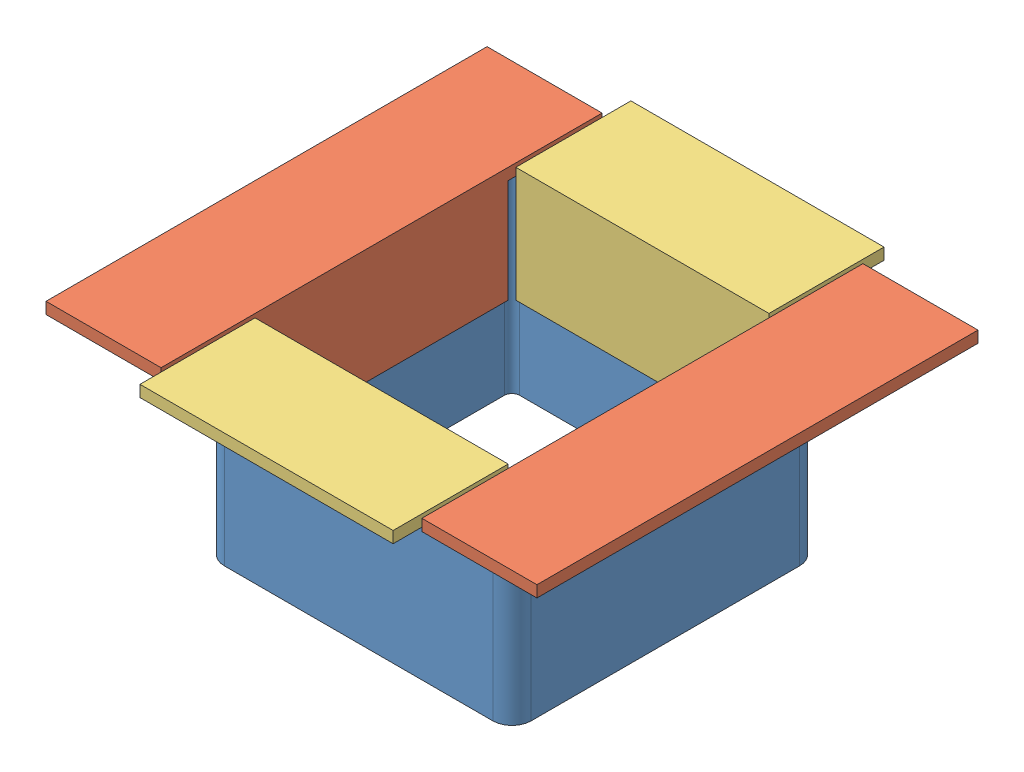
SolidWorks assembly ПяткаПСБ, configuration По умолчанию. Lengths in mm.
Overall size (128 54 128).
5 component instances, 3 part files, 6 mates.
Components (placement in the parent):
- Профиль80-1: Профиль80 [По умолчанию] at origin size (80 50 80)
- УголокДК2-1: УголокДК2 [По умолчанию] at (34 54 57.5) x (1 0 0) z (0 0 -1) size (30 30 115)
- УголокДК2-3: УголокДК2 [По умолчанию] at (-34 54 -57.5) x (-1 0 0) z (0 0 1) size (30 30 115)
- УголокДК1-1: УголокДК1 [По умолчанию] at (-33 54 34) x (0 0 1) z (1 0 0) size (30 30 66)
- УголокДК1-2: УголокДК1 [По умолчанию] at (33 54 -34) x (0 0 -1) z (-1 0 0) size (30 30 66)
Mates (geometry in assembly coordinates):
- Совпадение2: coincident anti-aligned: plane of Профиль80-1 through (37 50 -35) normal (-1 0 0); plane of УголокДК2-1 through (37 24 -61.5) normal (1 0 0)
- Расстояние1: distance = 1 mm anti-aligned: plane of УголокДК2-1 through (37 51 -57.5) normal (0 -1 0); plane of Профиль80-1 through (-35 50 35) normal (0 1 0)
- Совпадение4: coincident anti-aligned: plane of Профиль80-1 through (-35 50 37) normal (0 0 -1); plane of УголокДК1-1 through (33 24 37) normal (0 0 1)
- Совпадение5: coincident aligned: plane of УголокДК2-3 through (-34 54 61.5) normal (0 1 0); plane of УголокДК1-1 through (33 54 34) normal (0 1 0)
- Расстояние2: distance = 7 mm aligned: plane of УголокДК2-3 through (-64 24 -33) normal (0 0 -1); plane of Профиль80-1 through (-35 50 -40) normal (0 0 -1)
- Расстояние3: distance = 7 mm aligned: plane of УголокДК1-1 through (-33 54 34) normal (-1 0 0); plane of Профиль80-1 through (-40 50 -35) normal (-1 0 0)
